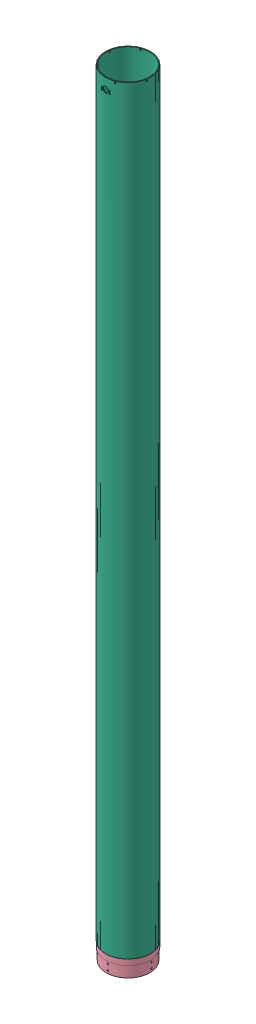
SolidWorks assembly 10005-R02_ASSEMBLY_PRESSURANT_BULK_HEAD, configuration Default. Lengths in mm.
Overall size (226.67 2331.82 226.67).
9 component instances, 6 part files, 17 mates.
Components (placement in the parent):
- 15001-R02_PRESSURANT_TANK-1: 15001-R02_PRESSURANT_TANK [Default] at (721.8624 220.7881 1650.156) size (158.75 2171.88 158.75)
- 15002-R01_PRESSURANT_TANK_RETAINER-1: 15002-R01_PRESSURANT_TANK_RETAINER [Default] at (814.5569 2297.4159 1599.4173) x (0.000836 0 -1) z (1 0 0.000836) size (177.8 6.35 177.8)
- 15005-R02_PRESSURANT_TANK_BULKHEAD_TOP-1: 15005-R02_PRESSURANT_TANK_BULKHEAD_TOP [Default] at (721.8624 2364.0909 1650.156) x (1 0 0.000214) z (-0.000214 0 1) size (226.62 63.5 226.62)
- 15006-R03_PRESSURANT_TANK_BULKHEAD_BOT-1: 15006-R03_PRESSURANT_TANK_BULKHEAD_BOT [Default] at (721.8624 95.775 1650.156) x (0.997046 0 -0.076804) z (0.076804 0 0.997046) size (203.2 127 203.2)
- 16001-R01_THREADED_ROD-1: 16001-R01_THREADED_ROD [Default] at (775.7324 2297.4159 1704.049) size (9.53 101.6 9.53)
- 16001-R01_THREADED_ROD-2: 16001-R01_THREADED_ROD [Default] at (667.9693 2297.4159 1704.026) size (9.53 101.6 9.53)
- 16001-R01_THREADED_ROD-3: 16001-R01_THREADED_ROD [Default] at (667.9924 2297.4159 1596.2629) size (9.53 101.6 9.53)
- 16001-R01_THREADED_ROD-4: 16001-R01_THREADED_ROD [Default] at (775.7554 2297.4159 1596.286) size (9.53 101.6 9.53)
- 14007-R03_UPPER_AIRFRAME-1: 14007-R03_UPPER_AIRFRAME [Default] at (721.8624 171.975 1650.156) size (203.2 3429 203.2) (hidden)
Mates (geometry in assembly coordinates):
- Concentric2: concentric: cylinder of 15001-R02_PRESSURANT_TANK-1 through (721.8624 2233.9159 1650.156) axis (0 -1 0) radius 79.375; cylinder of 15006-R03_PRESSURANT_TANK_BULKHEAD_BOT-1 through (721.8624 159.275 1650.156) axis (0 1 0) radius 95.25
- Concentric3: concentric: cylinder of 15001-R02_PRESSURANT_TANK-1 through (721.8624 2233.9159 1650.156) axis (0 -1 0) radius 79.375; cylinder of 15002-R01_PRESSURANT_TANK_RETAINER-1 through (721.8624 2303.7659 1650.156) axis (0 -1 0) radius 88.9
- Tangent5: tangent: sphere of 15001-R02_PRESSURANT_TANK-1; circle of 15002-R01_PRESSURANT_TANK_RETAINER-1
- Tangent6: tangent: sphere of 15001-R02_PRESSURANT_TANK-1; circle of 15006-R03_PRESSURANT_TANK_BULKHEAD_BOT-1
- Concentric4: concentric: cylinder of 15002-R01_PRESSURANT_TANK_RETAINER-1 through (721.8624 2303.7659 1650.156) axis (0 -1 0) radius 88.9; cylinder of 15005-R02_PRESSURANT_TANK_BULKHEAD_TOP-1 through (721.8624 2427.5909 1650.156) axis (0 -1 0) radius 98.425
- Coincident1: coincident: plane of 16001-R01_THREADED_ROD-3 through (667.9924 2399.0159 1596.2629) normal (0 1 0); plane of 16001-R01_THREADED_ROD-4 through (775.7554 2399.0159 1596.286) normal (0 1 0)
- Concentric5: concentric: circle of 15005-R02_PRESSURANT_TANK_BULKHEAD_TOP-1; circle of 16001-R01_THREADED_ROD-2
- Concentric6: concentric: cylinder of 15005-R02_PRESSURANT_TANK_BULKHEAD_TOP-1 through (775.7324 2364.0899 1704.049) axis (0 1 0) radius 4.826; circle of 16001-R01_THREADED_ROD-1
- Concentric7: concentric: circle of 15005-R02_PRESSURANT_TANK_BULKHEAD_TOP-1; circle of 16001-R01_THREADED_ROD-4
- Concentric8: concentric: circle of 15005-R02_PRESSURANT_TANK_BULKHEAD_TOP-1; circle of 16001-R01_THREADED_ROD-3
- Coincident3: coincident: plane of 15002-R01_PRESSURANT_TANK_RETAINER-1 through (721.8624 2297.4159 1650.156) normal (0 -1 0); circle of 16001-R01_THREADED_ROD-1
- Coincident4: coincident: plane of 15005-R02_PRESSURANT_TANK_BULKHEAD_TOP-1 through (721.8624 2399.0159 1650.156) normal (0 1 0); plane of 16001-R01_THREADED_ROD-1 through (775.7324 2399.0159 1704.049) normal (0 1 0)
- Coincident5: coincident: plane of 15005-R02_PRESSURANT_TANK_BULKHEAD_TOP-1 through (721.8624 2399.0159 1650.156) normal (0 1 0); plane of 16001-R01_THREADED_ROD-4 through (775.7554 2399.0159 1596.286) normal (0 1 0)
- Coincident6: coincident: plane of 15005-R02_PRESSURANT_TANK_BULKHEAD_TOP-1 through (721.8624 2399.0159 1650.156) normal (0 1 0); plane of 16001-R01_THREADED_ROD-2 through (667.9693 2399.0159 1704.026) normal (0 1 0)
- Coincident7: coincident: circle of 15002-R01_PRESSURANT_TANK_RETAINER-1; circle of 16001-R01_THREADED_ROD-1
- Coincident8: coincident: plane of 15006-R03_PRESSURANT_TANK_BULKHEAD_BOT-1 through (721.8624 171.975 1650.156) normal (0 1 0); plane of 14007-R03_UPPER_AIRFRAME-1 through (721.8624 171.975 1650.156) normal (0 -1 0)
- Concentric9: concentric: cylinder of 15006-R03_PRESSURANT_TANK_BULKHEAD_BOT-1 through (721.8624 222.775 1650.156) axis (0 -1 0) radius 101.6; cylinder of 14007-R03_UPPER_AIRFRAME-1 through (721.8624 3600.975 1650.156) axis (0 -1 0) radius 101.6
